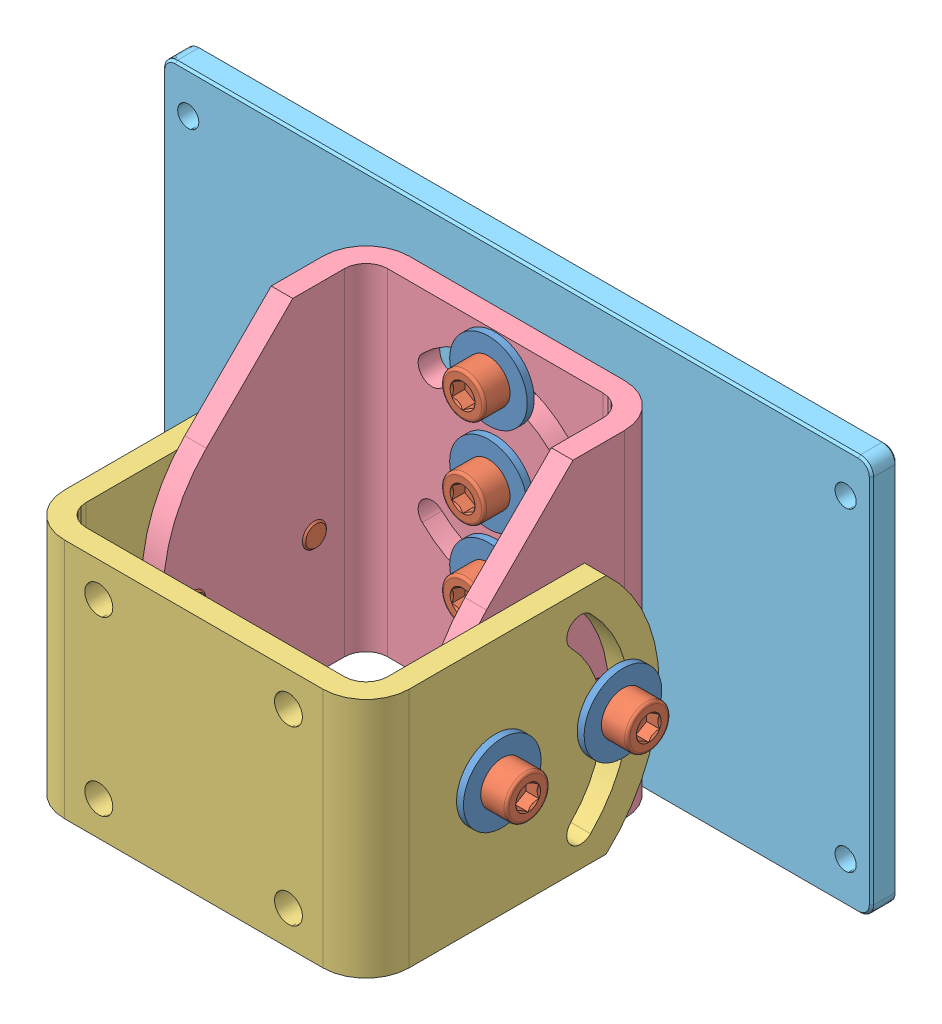
SolidWorks assembly LD_Brace, configuration Default. Lengths in mm.
Overall size (164.5 92 83).
18 component instances, 5 part files, 4 mates.
Components (placement in the parent):
- LD_Brace_P2-1: LD_Brace_P2 [Default] at (-8.8144 13.0348 -106.0147) size (95.76 78 80.4)
  - 5310226_Scheibe_6.4_DIN9021_A2.2_1-1: 5310226_Scheibe_6.4_DIN9021_A2.2_1 [Default] at (0 15.8126 61.1) x (1 0 0) z (0 -1 0) size (18 1.6 18)
  - 5321646_DIN_EN_ISO4762_M6x12.2-1: 5321646_DIN_EN_ISO4762_M6x12.2 [Default] at (166.5438 358.5597 -321.0466) x (0 0 -1) z (-1 0 0) size (10 10 18.28)
  - 5321646_DIN_EN_ISO4762_M6x12.2-2: 5321646_DIN_EN_ISO4762_M6x12.2 [Default] at (-166.5438 358.5597 556.0466) x (0 0 1) z (1 0 0) size (10 10 18.28)
  - 5321646_DIN_EN_ISO4762_M6x12.2-3: 5321646_DIN_EN_ISO4762_M6x12.2 [Default] at (-166.5438 358.5597 528.0466) x (0 0 1) z (1 0 0) size (10 10 18.28)
  - 5321646_DIN_EN_ISO4762_M6x12.2-4: 5321646_DIN_EN_ISO4762_M6x12.2 [Default] at (424.5466 357.8097 218.0438) x (1 0 0) z (0 0 -1) size (10 10 18.28)
  - 5321646_DIN_EN_ISO4762_M6x12.2-5: 5321646_DIN_EN_ISO4762_M6x12.2 [Default] at (424.5466 378.5597 218.0438) x (1 0 0) z (0 0 -1) size (10 10 18.28)
  - 5321646_DIN_EN_ISO4762_M6x12.2-6: 5321646_DIN_EN_ISO4762_M6x12.2 [Default] at (166.5438 358.5597 -293.0466) x (0 0 -1) z (-1 0 0) size (10 10 18.28)
  - 5310226_Scheibe_6.4_DIN9021_A2.2_1-2: 5310226_Scheibe_6.4_DIN9021_A2.2_1 [Default] at (-9.6 -24.9374 103.5) x (0 0 1) z (0 -1 0) size (18 1.6 18)
  - 5310226_Scheibe_6.4_DIN9021_A2.2_1-3: 5310226_Scheibe_6.4_DIN9021_A2.2_1 [Default] at (9.6 -24.9374 103.5) x (0 0 -1) z (0 -1 0) size (18 1.6 18)
  - 4054296_Winkelflansch_Anlage_1-1: 4054296_Winkelflansch_Anlage_1 [Default] at (0 -33 25) size (80 56 68)
  - 5310226_Scheibe_6.4_DIN9021_A2.2_1-4: 5310226_Scheibe_6.4_DIN9021_A2.2_1 [Default] at (9.6 -24.9374 131.5) x (0 0 -1) z (0 -1 0) size (18 1.6 18)
  - 5321646_DIN_EN_ISO4762_M6x12.2-7: 5321646_DIN_EN_ISO4762_M6x12.2 [Default] at (424.5466 399.3097 218.0438) x (1 0 0) z (0 0 -1) size (10 10 18.28)
  - 5310226_Scheibe_6.4_DIN9021_A2.2_1-5: 5310226_Scheibe_6.4_DIN9021_A2.2_1 [Default] at (-9.6 -24.9374 131.5) x (0 0 1) z (0 -1 0) size (18 1.6 18)
  - 5310226_Scheibe_6.4_DIN9021_A2.2_1-6: 5310226_Scheibe_6.4_DIN9021_A2.2_1 [Default] at (0 -4.9374 61.1) x (1 0 0) z (0 -1 0) size (18 1.6 18)
  - 5310226_Scheibe_6.4_DIN9021_A2.2_1-7: 5310226_Scheibe_6.4_DIN9021_A2.2_1 [Default] at (0 -25.6874 61.1) x (1 0 0) z (0 -1 0) size (18 1.6 18)
  - 4054298_Winkelflansch_Wetterschutzhaube_1-1: 4054298_Winkelflansch_Wetterschutzhaube_1 [Default] at (0 -13 20) size (70 78 52)
- LD_Brace_P1-1: LD_Brace_P1 [Default] at (-8.8144 -10.6526 -22.5147) size (164.5 92 8)
Mates (geometry in assembly coordinates):
- Concentric1: concentric anti-aligned: cylinder of LD_Brace_P2-1/5321646_DIN_EN_ISO4762_M6x12.2-7 through (-8.8144 14.0974 -14.4147) axis (0 0 -1) radius 3; cylinder of LD_Brace_P1-1 through (-8.8144 14.0974 -19.5147) axis (0 0 1) radius 2.5
- Concentric2: concentric anti-aligned: cylinder of LD_Brace_P2-1/5321646_DIN_EN_ISO4762_M6x12.2-5 through (-8.8144 -6.6526 -14.4147) axis (0 0 -1) radius 3; cylinder of LD_Brace_P1-1 through (-8.8144 -6.6526 -19.5147) axis (0 0 1) radius 2.5
- Concentric3: concentric anti-aligned: cylinder of LD_Brace_P2-1/5321646_DIN_EN_ISO4762_M6x12.2-4 through (-8.8144 -27.4026 -14.4147) axis (0 0 -1) radius 3; cylinder of LD_Brace_P1-1 through (-8.8144 -27.4026 -19.5147) axis (0 0 1) radius 2.5
- Coincident1: coincident anti-aligned: plane of LD_Brace_P2-1/4054298_Winkelflansch_Wetterschutzhaube_1-1 through (2.3788 19.7935 -19.5147) normal (0 0 -1); plane of LD_Brace_P1-1 through (-8.8144 -10.6526 -19.5147) normal (0 0 1)
